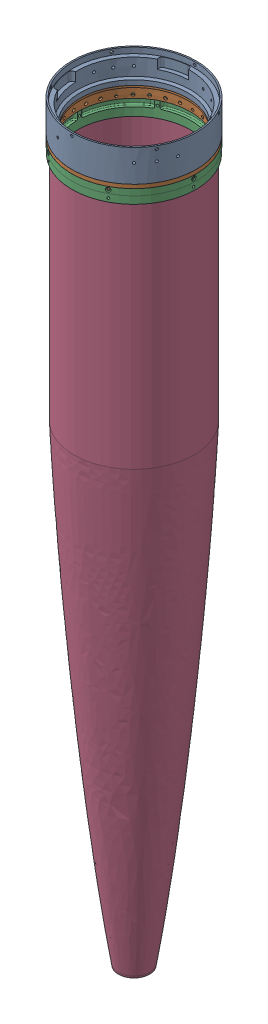
SolidWorks assembly Rings, configuration Default. Lengths in mm.
Overall size (231.42 1013.46 231.42).
4 component instances, 4 part files, 6 mates.
Components (placement in the parent):
- NSRlower 2.0v5-1: NSRlower 2.0v5 [Default] at origin size (167.64 43 167.64)
- NSRupper2.0v5-1: NSRupper2.0v5 [Default] at (-12.5677 -172.4949 -51.5166) x (0.843784 0 0.536683) z (0.536683 0 -0.843784) size (167.64 17.78 167.64)
- femaleRing-1: femaleRing [Default] at (-35.6788 -12.7 -67.331) x (0 -1 0) z (0.468225 0 0.883609) size (28.7 167.64 167.64)
- nosecone-1: nosecone [Default] at (0 -1066.1417 0) x (0 1 0) z (0.764543 0 0.644573) size (946.84 161.29 161.29)
Mates (geometry in assembly coordinates):
- Concentric40: concentric anti-aligned: cylinder of NSRlower 2.0v5-1 through (0 0 0) axis (0 -1 0) radius 83.82; cylinder of NSRupper2.0v5-1 through (0 -10.4197 0) axis (0 1 0) radius 83.82
- Coincident26: coincident anti-aligned: plane of NSRlower 2.0v5-1 through (-83.82 0 0) normal (0 -1 0); plane of NSRupper2.0v5-1 through (39.1037 0 74.1397) normal (0 1 0)
- Concentric41: concentric anti-aligned: cylinder of NSRlower 2.0v5-1 through (0 0 0) axis (0 -1 0) radius 83.82; cylinder of femaleRing-1 through (0 -6.35 0) axis (0 1 0) radius 83.82
- Concentric43: concentric aligned: cylinder of NSRlower 2.0v5-1 through (0 0 0) axis (0 -1 0) radius 83.82; cylinder of nosecone-1 through (0 -1066.1417 0) axis (0 -1 0) radius 80.645
- Coincident27: coincident anti-aligned: plane of NSRupper2.0v5-1 through (39.1037 -5.08 74.1397) normal (0 -1 0); plane of femaleRing-1 through (-35.6788 -5.08 -67.331) normal (0 1 0)
- Coincident40: coincident aligned: plane of femaleRing-1 through (-35.6788 -23.622 -67.331) normal (0 -1 0); circle of nosecone-1
